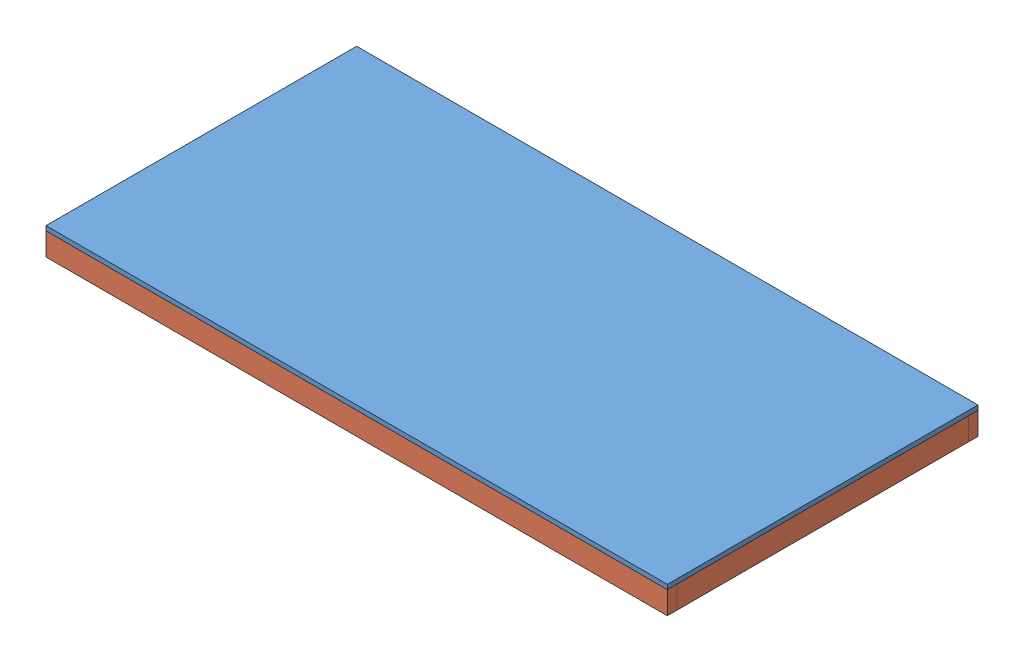
SolidWorks assembly Platform Top, configuration Default. Lengths in mm.
Overall size (2438.4 106.76 1219.2).
10 component instances, 2 part files, 7 mates.
Components (placement in the parent):
- 4x8-1: 4x8 [Default] at origin size (2438.4 17.86 1219.2)
- 2x4 Configurable-6: 2x4 Configurable [96" Long] at (0 -53.3781 590.55) x (1 0 0) z (0 0 -1) size (2438.4 88.9 38.1)
- 2x4 Configurable-7: 2x4 Configurable [96" Long] at (0 -53.3781 -590.55) x (1 0 0) z (0 0 -1) size (2438.4 88.9 38.1)
- 2x4 Configurable-10: 2x4 Configurable [45" Long] at (-1200.15 -53.3781 0) x (0 0 -1) z (1 0 0) size (1143 88.9 38.1)
- 2x4 Configurable-11: 2x4 Configurable [45" Long] at (-800.1 -53.3781 0) x (0 0 -1) z (1 0 0) size (1143 88.9 38.1)
- 2x4 Configurable-12: 2x4 Configurable [45" Long] at (-400.05 -53.3781 0) x (0 0 -1) z (1 0 0) size (1143 88.9 38.1)
- 2x4 Configurable-13: 2x4 Configurable [45" Long] at (0 -53.3781 0) x (0 0 -1) z (1 0 0) size (1143 88.9 38.1)
- 2x4 Configurable-14: 2x4 Configurable [45" Long] at (400.05 -53.3781 0) x (0 0 -1) z (1 0 0) size (1143 88.9 38.1)
- 2x4 Configurable-15: 2x4 Configurable [45" Long] at (800.1 -53.3781 0) x (0 0 -1) z (1 0 0) size (1143 88.9 38.1)
- 2x4 Configurable-16: 2x4 Configurable [45" Long] at (1200.15 -53.3781 0) x (0 0 -1) z (1 0 0) size (1143 88.9 38.1)
Mates (geometry in assembly coordinates):
- Coincident1: coincident anti-aligned: line of 4x8-1 through (-1219.2 -8.9281 -609.6) axis (0 0 1); line of 2x4 Configurable-6 through (-1219.2 -8.9281 609.6) axis (0 0 -1)
- Coincident2: coincident aligned: line of 4x8-1 through (-1219.2 -8.9281 609.6) axis (1 0 0); line of 2x4 Configurable-6 through (-1219.2 -8.9281 609.6) axis (1 0 0)
- Coincident3: coincident anti-aligned: line of 4x8-1 through (-1219.2 -8.9281 -609.6) axis (0 0 1); line of 2x4 Configurable-7 through (-1219.2 -8.9281 -571.5) axis (0 0 -1)
- Coincident4: coincident anti-aligned: line of 4x8-1 through (1219.2 -8.9281 -609.6) axis (-1 0 0); line of 2x4 Configurable-7 through (-1219.2 -8.9281 -609.6) axis (1 0 0)
- Coincident6: coincident anti-aligned: plane of 4x8-1 through (0 -8.9281 0) normal (0 -1 0); plane of 2x4 Configurable-10 through (-1219.2 -8.9281 571.5) normal (0 1 0)
- Coincident7: coincident anti-aligned: plane of 2x4 Configurable-7 through (0 -53.3781 -571.5) normal (0 0 1); plane of 2x4 Configurable-10 through (-1219.2 -8.9281 -571.5) normal (0 0 -1)
- Coincident8: coincident aligned: line of 4x8-1 through (-1219.2 -8.9281 -609.6) axis (0 0 1); line of 2x4 Configurable-10 through (-1219.2 -8.9281 -571.5) axis (0 0 1)
